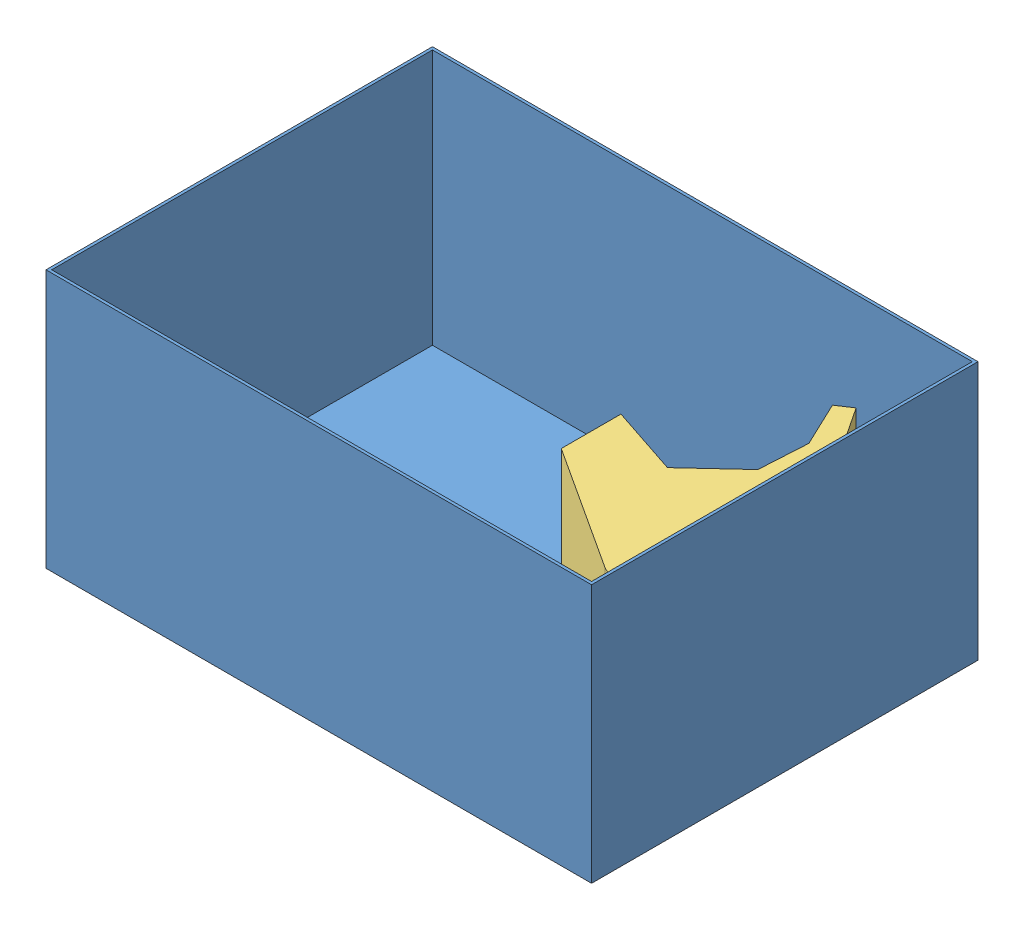
SolidWorks assembly Kiste, configuration Standard. Lengths in mm.
Overall size (384 182 272).
3 component instances, 3 part files, 8 mates.
Components (placement in the parent):
- metabox-215-1: metabox-215 [Standard] at (108.3633 -92.8434 518) size (384 182 272)
- Halter-LED-1: Halter-LED [Standard] at (92.8633 -89.6434 488.8201) x (0 0 1) z (0 -1 0) size (200.95 105.5 11.2)
- LED-Lampe-3: LED-Lampe [Standard] at (92.8633 65.3566 488.8201) x (0 0 1) z (0 -1 0) size (187.2 101.5 155)
Mates (geometry in assembly coordinates):
- Parallel2: parallel anti-aligned: plane of metabox-215-1 through (108.3633 -92.8434 250) normal (-1 0 0); plane of ? through (101.9856 -90.2434 495.9821) normal (1 0 0)
- Deckungsgleich1: coincident anti-aligned: plane of metabox-215-1 through (108.3633 -90.8434 518) normal (0 1 0); plane of Halter-LED-1 through (92.8633 -90.8434 488.8201) normal (0 -1 0)
- Parallel3: parallel aligned: plane of metabox-215-1 through (108.3633 -92.8434 250) normal (-1 0 0); plane of Halter-LED-1 through (94.8633 -79.6434 445) normal (-1 0 0)
- Abstand1: distance = 10 mm anti-aligned: plane of Halter-LED-1 through (98.3633 -79.6434 470.5) normal (1 0 0); plane of metabox-215-1 through (108.3633 -92.8434 250) normal (-1 0 0)
- Abstand2: distance = 50 mm aligned: plane of Halter-LED-1 through (94.8633 -79.6434 468) normal (0 0 -1); plane of metabox-215-1 through (-271.6367 -92.8434 518) normal (0 0 -1)
- Deckungsgleich5: coincident: plane of Halter-LED-1 through (92.8633 -89.6434 488.8201) normal (0 1 0); plane of LED-Lampe-3 through (85.3633 -89.6434 475) normal (0 -1 0)
- Abstand3: distance = 0.5 mm: plane of LED-Lampe-3 through (94.3633 -89.6434 467.5) normal (1 0 0); plane of Halter-LED-1 through (94.8633 -79.6434 445) normal (-1 0 0)
- Abstand4: distance = 0.5 mm anti-aligned: plane of LED-Lampe-3 through (92.8633 -89.6434 467.5) normal (0 0 1); plane of Halter-LED-1 through (94.8633 -79.6434 468) normal (0 0 -1)
